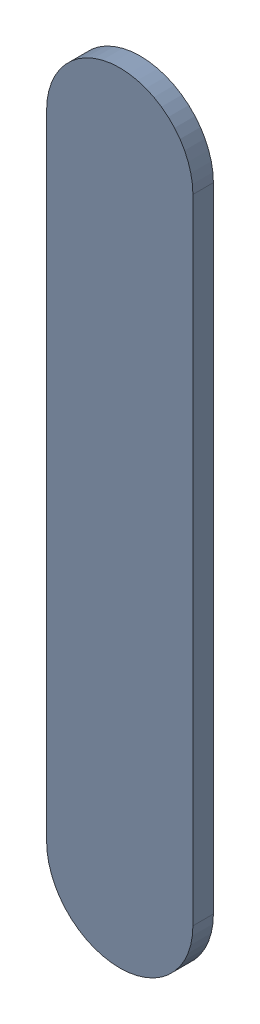
SolidWorks assembly Track (27.8mm,42.4mm)(27.8mm,43.5mm) on Top Layer, configuration Predeterminado. Lengths in mm.
Overall size (0.25 1.35 0.04).
2 component instances, 1 part files, 0 mates.
Components (placement in the parent):
- Track (27.8mm,42.4mm)(27.8mm,43.5mm) on Top Layer-1-1: Track (27.8mm,42.4mm)(27.8mm,43.5mm) on Top Layer-1 [Predeterminado] at (-68.317 -44.187 -0.0457) size (0.25 1.35 0.04)
  - Track (27.8mm,42.4mm)(27.8mm,43.5mm) on Top Layer-Part-1-1: Track (27.8mm,42.4mm)(27.8mm,43.5mm) on Top Layer-Part-1 [Predeterminado] at origin size (0.25 1.35 0.04)
